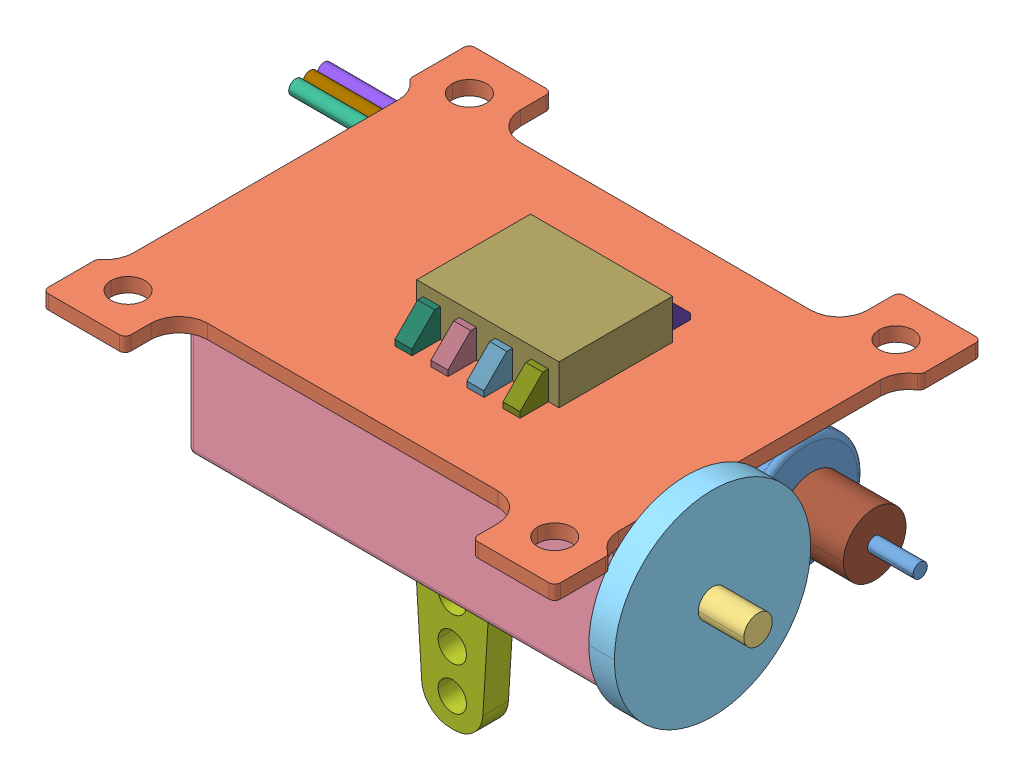
SolidWorks assembly servo, configuration Default. Lengths in mm.
Overall size (23.76 12.15 15).
21 component instances, 20 part files, 0 mates.
Components (placement in the parent):
- servo.stp-1: servo.stp [Default] at origin size (23.76 12.15 15)
  - Block 01.stp-1: Block 01.stp [Default] at (49.925 -22.475 8.625) x (0 0 -1) z (-1 0 0) size (4.01 4.01 15.31)
  - Document.stp-1: Document.stp [Default] at origin size (18 0.5 15)
  - Document-0.stp-1: Document-0.stp [Default] at origin size (2.7 1 1)
  - Document-1.stp-1: Document-1.stp [Default] at origin size (14.95 4.5 4.8)
  - Document-2.stp-1: Document-2.stp [Default] at origin size (0.9 6.9 6.9)
  - Document-3.stp-1: Document-3.stp [Default] at origin size (5 0.51 0.51)
  - Document-4.stp-1: Document-4.stp [Default] at origin size (3 7.75 0.9)
  - Document-5.stp-1: Document-5.stp [Default] at origin size (5 0.51 0.51)
  - Document-6.stp-1: Document-6.stp [Default] at origin size (5 0.51 0.51)
  - Document-7.stp-1: Document-7.stp [Default] at origin size (1.2 2.3 2.3)
  - Document-8.stp-1: Document-8.stp [Default] at origin size (2.2 2.2 2.2)
  - Document-9.stp-1: Document-9.stp [Default] at origin size (5 1.4 4)
  - Document-10.stp-1: Document-10.stp [Default] at origin size (0.6 1 1)
  - Document-11.stp-1: Document-11.stp [Default] at origin size (0.6 1 1)
  - Document-12.stp-1: Document-12.stp [Default] at origin size (0.6 1 1)
  - Document-13.stp-1: Document-13.stp [Default] at origin size (0.6 1 1)
  - Document-14.stp-1: Document-14.stp [Default] at origin size (0.6 1 1)
  - Document-15.stp-1: Document-15.stp [Default] at origin size (0.6 1 1)
  - Document-16.stp-1: Document-16.stp [Default] at origin size (0.6 1 1)
  - Document-17.stp-1: Document-17.stp [Default] at origin size (0.6 1 1)
